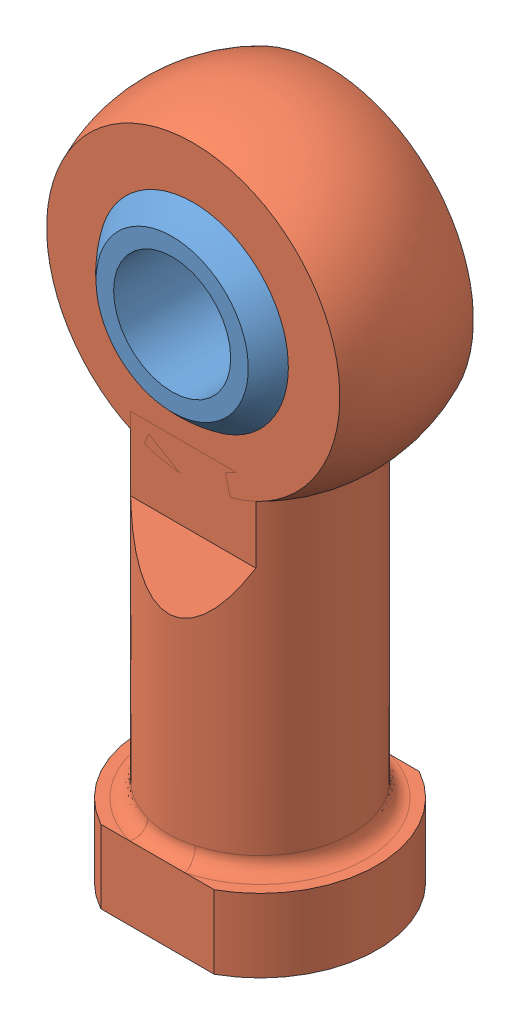
SolidWorks assembly RodEnd8mmFem, configuration Default. Lengths in mm.
Overall size (22 47 22.2).
2 component instances, 2 part files, 1 mates.
Components (placement in the parent):
- RodEndBall8mm-1: RodEndBall8mm [Default] at origin size (15.88 15.88 22.2)
- RodEndRace8mmFem-1: RodEndRace8mmFem [Default] at origin size (22 47 14)
Mates (geometry in assembly coordinates):
- Concentric1: concentric: sphere of ?; unknown of ?
